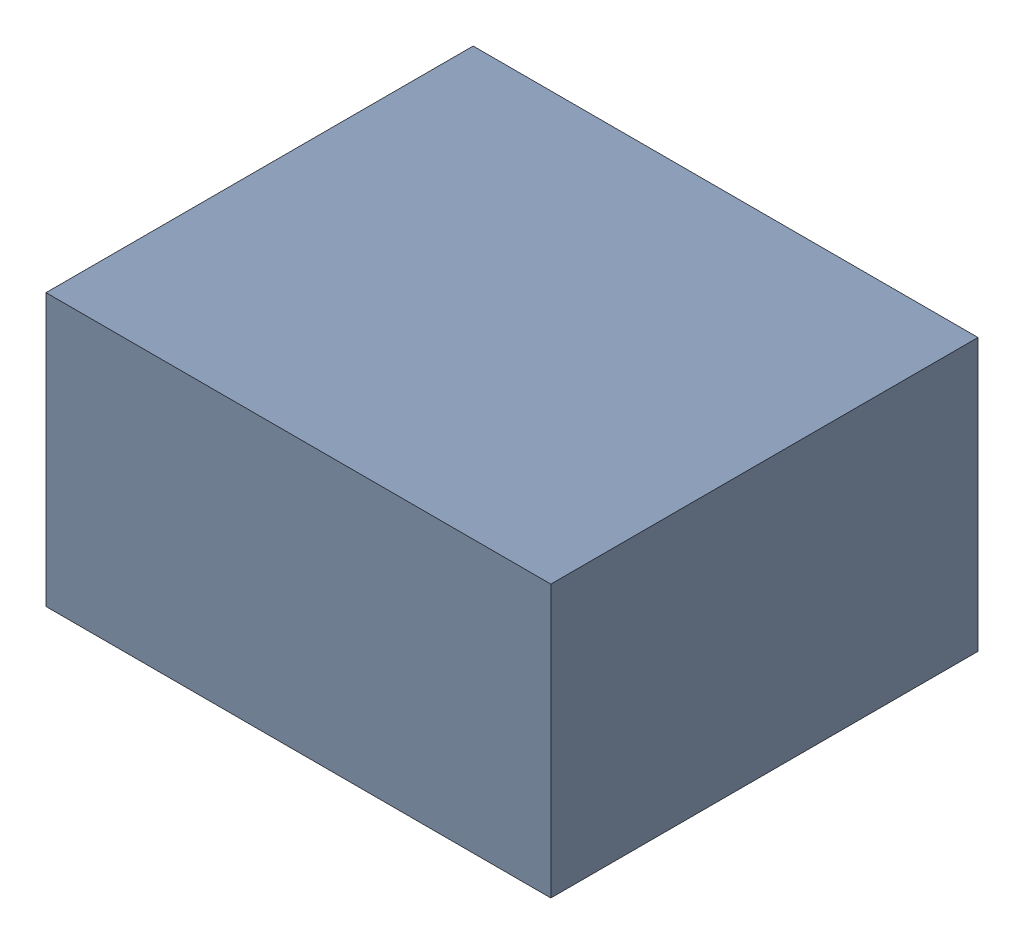
SolidWorks assembly L11, configuration Standard. Lengths in mm.
Overall size (0.65 0.35 0.55).
2 component instances, 1 part files, 0 mates.
Components (placement in the parent):
- 885541696-1: 885541696 [Standard] at (-20.25 3 0) size (0.65 0.35 0.55)
  - Extruded_32-1: Extruded_32 [Standard] at origin size (0.65 0.35 0.55)
